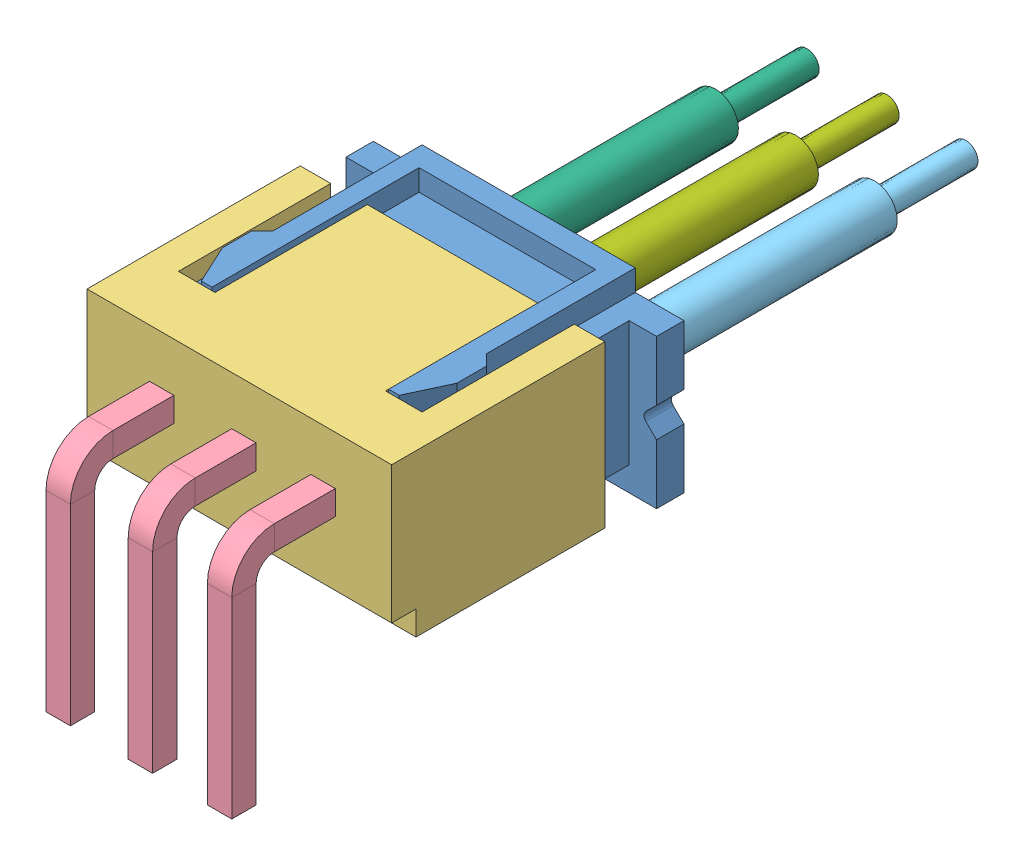
SolidWorks assembly JST(XH) 3Pin , configuration Default. Lengths in mm.
Overall size (10.2 9.6 24.55).
11 component instances, 7 part files, 21 mates.
Components (placement in the parent):
- JST - XH MALE 2S-1: JST - XH MALE 2S [Défaut] at (2.2896 3.6858 9.7425) size (10.2 5.6 7.9)
- Part1-3: Part1 [Default] at (4.9896 3.7858 8.5925) x (1 0 0) z (0 1 0) size (1.8 6 3.23)
- Part1-5: Part1 [Default] at (-0.2104 3.7858 8.5925) x (1 0 0) z (0 1 0) size (1.8 6 3.23)
- Part1-6: Part1 [Default] at (2.3896 3.7858 8.5925) x (1 0 0) z (0 1 0) size (1.8 6 3.23)
- Part 3-1: Part 3 [Default] at (2.2896 3.7358 4.4425) x (-1 0 0) z (0 1 0) size (10 7 5.3)
- Part3-1: Part3 [Default] at (5.0396 4.3858 14.4425) x (0 0 1) z (-1 0 0) size (9.7 7.9 0.8)
- Part3-2: Part3 [Default] at (2.4396 4.3858 14.4425) x (0 0 1) z (-1 0 0) size (9.7 7.9 0.8)
- Part3-3: Part3 [Default] at (-0.2604 4.3858 14.4425) x (0 0 1) z (-1 0 0) size (9.7 7.9 0.8)
- Part4-1: Part4 [Default] at (4.9954 3.4913 -6.7068) size (1.5 1.5 16)
- Part5-1: Part5 [Default] at (-0.2226 3.4901 -6.7085) size (1.5 1.5 16)
- Part6-1: Part6 [Default] at (2.4071 3.4964 -6.7068) size (1.5 1.5 16)
Mates (geometry in assembly coordinates):
- Width3: width anti-aligned: plane of Part1-3 through (4.0896 2.6358 6.4925) normal (-1 0 0); plane of Part1-3 through (5.8896 2.6358 6.4925) normal (1 0 0); plane of JST - XH MALE 2S-1 through (3.8896 3.6858 9.3425) normal (1 0 0); plane of JST - XH MALE 2S-1 through (6.0896 3.6858 9.3425) normal (-1 0 0)
- Distance1: distance = 0.75 mm anti-aligned: plane of JST - XH MALE 2S-1 through (2.2896 3.6858 9.3425) normal (0 0 -1); plane of Part1-3 through (4.9896 3.7858 8.5925) normal (0 0 1)
- Width6: width anti-aligned: plane of Part1-3 through (4.0896 2.6358 6.4925) normal (0 -1 0); plane of Part1-3 through (4.0896 4.9358 6.4925) normal (0 1 0); plane of JST - XH MALE 2S-1 through (2.2896 2.3858 9.3425) normal (0 1 0); plane of JST - XH MALE 2S-1 through (2.2896 5.1858 8.9425) normal (0 -1 0)
- Coincident1: coincident aligned: plane of Part1-3 through (4.9896 3.7858 8.5925) normal (0 0 1); plane of Part1-6 through (2.3896 3.7858 8.5925) normal (0 0 1)
- Width7: width aligned: plane of Part1-6 through (1.4896 2.6358 6.4925) normal (-1 0 0); plane of Part1-6 through (3.2896 2.6358 6.4925) normal (1 0 0); plane of JST - XH MALE 2S-1 through (3.4896 3.6858 9.3425) normal (-1 0 0); plane of JST - XH MALE 2S-1 through (1.2896 3.6858 9.3425) normal (1 0 0)
- Width9: width anti-aligned: plane of Part1-6 through (1.4896 2.6358 6.4925) normal (0 -1 0); plane of Part1-6 through (1.4896 4.9358 6.4925) normal (0 1 0); plane of JST - XH MALE 2S-1 through (2.2896 2.3858 9.3425) normal (0 1 0); plane of JST - XH MALE 2S-1 through (2.2896 5.1858 8.9425) normal (0 -1 0)
- Coincident2: coincident aligned: plane of Part1-5 through (-0.2104 3.7858 8.5925) normal (0 0 1); plane of Part1-6 through (2.3896 3.7858 8.5925) normal (0 0 1)
- Width10: width aligned: plane of Part1-5 through (0.6896 2.6358 6.4925) normal (1 0 0); plane of Part1-5 through (-1.1104 2.6358 6.4925) normal (-1 0 0); plane of JST - XH MALE 2S-1 through (-1.3104 3.6858 9.3425) normal (1 0 0); plane of JST - XH MALE 2S-1 through (0.8896 3.6858 9.3425) normal (-1 0 0)
- Width11: width aligned: plane of Part1-5 through (-1.1104 2.6358 6.4925) normal (0 -1 0); plane of Part1-5 through (-1.1104 4.9358 6.4925) normal (0 1 0); plane of JST - XH MALE 2S-1 through (2.2896 5.1858 8.9425) normal (0 -1 0); plane of JST - XH MALE 2S-1 through (2.2896 2.3858 9.3425) normal (0 1 0)
- Width12: width anti-aligned: plane of Part 3-1 through (-2.1104 1.7358 9.4425) normal (1 0 0); plane of Part 3-1 through (6.6896 1.7358 9.4425) normal (-1 0 0); plane of JST - XH MALE 2S-1 through (-1.9104 3.6858 2.8425) normal (-1 0 0); plane of JST - XH MALE 2S-1 through (6.4896 3.6858 2.8425) normal (1 0 0)
- Width13: width anti-aligned: plane of Part 3-1 through (6.6896 5.7358 9.4425) normal (0 -1 0); plane of Part 3-1 through (6.6896 1.7358 9.4425) normal (0 1 0); plane of JST - XH MALE 2S-1 through (2.2896 5.7858 9.7425) normal (0 1 0); plane of JST - XH MALE 2S-1 through (2.2896 1.6858 2.8425) normal (0 -1 0)
- LimitDistance1: limit distance = 0 mm anti-aligned: plane of JST - XH MALE 2S-1 through (2.2896 3.6858 9.4425) normal (0 0 1); plane of Part 3-1 through (2.2896 3.7358 9.4425) normal (0 0 -1)
- Coincident4: coincident anti-aligned: plane of Part 3-1 through (4.6396 4.7858 1.4425) normal (0 -1 0); plane of Part3-1 through (5.4396 4.7858 13.4425) normal (0 1 0)
- Coincident5: coincident anti-aligned: plane of Part 3-1 through (5.4396 4.7858 1.4425) normal (-1 0 0); plane of Part3-1 through (5.4396 4.7858 13.4425) normal (1 0 0)
- Distance3: distance = 0.7 mm aligned: plane of Part3-1 through (5.0396 4.3858 5.1425) normal (0 0 -1); plane of Part 3-1 through (2.2896 3.7358 4.4425) normal (0 0 -1)
- Coincident7: coincident aligned: plane of Part3-2 through (2.8396 3.3858 14.8425) normal (0 0 1); plane of Part3-3 through (0.1396 3.3858 14.8425) normal (0 0 1)
- Coincident8: coincident aligned: plane of Part3-1 through (5.4396 3.3858 14.8425) normal (0 0 1); plane of Part3-2 through (2.8396 3.3858 14.8425) normal (0 0 1)
- Coincident9: coincident anti-aligned: plane of Part 3-1 through (2.8396 4.7858 1.4425) normal (-1 0 0); plane of Part3-2 through (2.8396 4.7858 13.4425) normal (1 0 0)
- Coincident10: coincident anti-aligned: plane of Part 3-1 through (2.0396 4.7858 1.4425) normal (0 -1 0); plane of Part3-2 through (2.8396 4.7858 13.4425) normal (0 1 0)
- Coincident11: coincident anti-aligned: plane of Part 3-1 through (0.1396 4.7858 1.4425) normal (-1 0 0); plane of Part3-3 through (0.1396 4.7858 13.4425) normal (1 0 0)
- Coincident13: coincident anti-aligned: plane of Part 3-1 through (-0.6604 4.7858 1.4425) normal (0 -1 0); plane of Part3-3 through (0.1396 4.7858 13.4425) normal (0 1 0)
